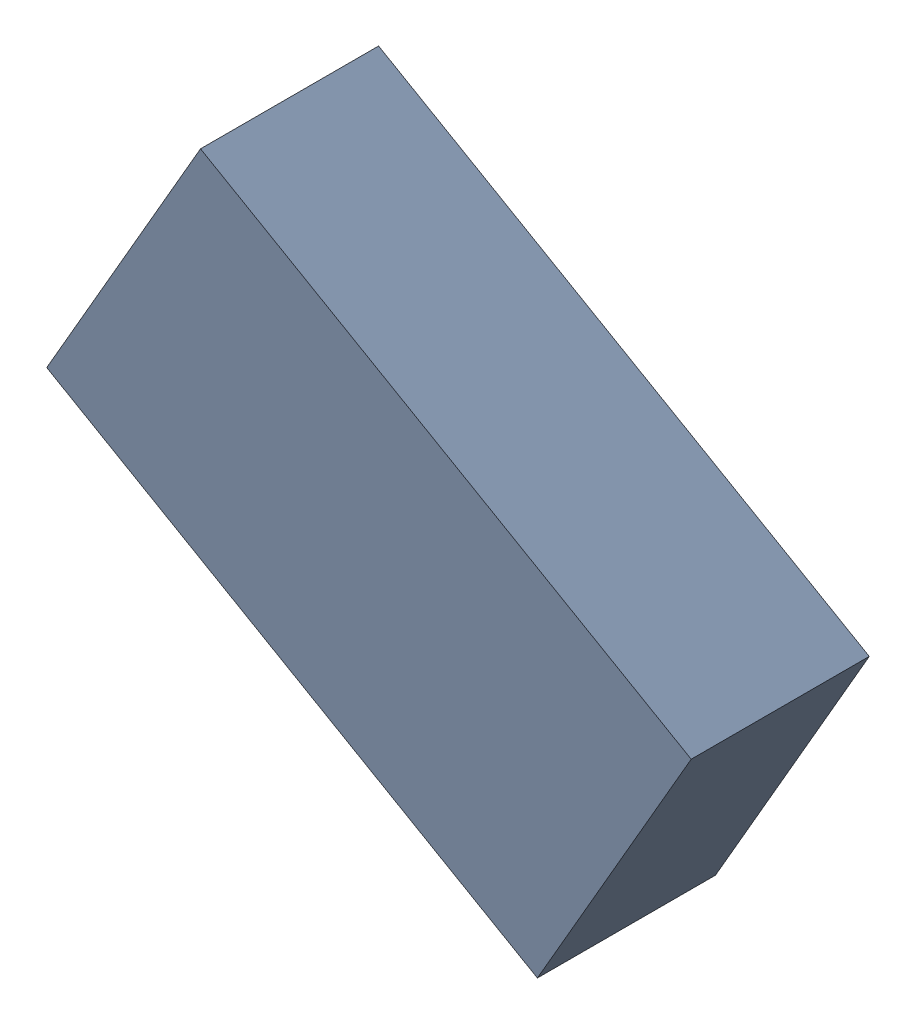
SolidWorks assembly L2_TDA6, configuration Standard. Lengths in mm.
Overall size (1.99 1.7 0.55).
2 component instances, 1 part files, 0 mates.
Components (placement in the parent):
- 885543872-1: 885543872 [Standard] at (-49.792 33.6101 0) size (1.99 1.7 0.55)
  - Extruded_20-1: Extruded_20 [Standard] at origin size (1.99 1.7 0.55)
